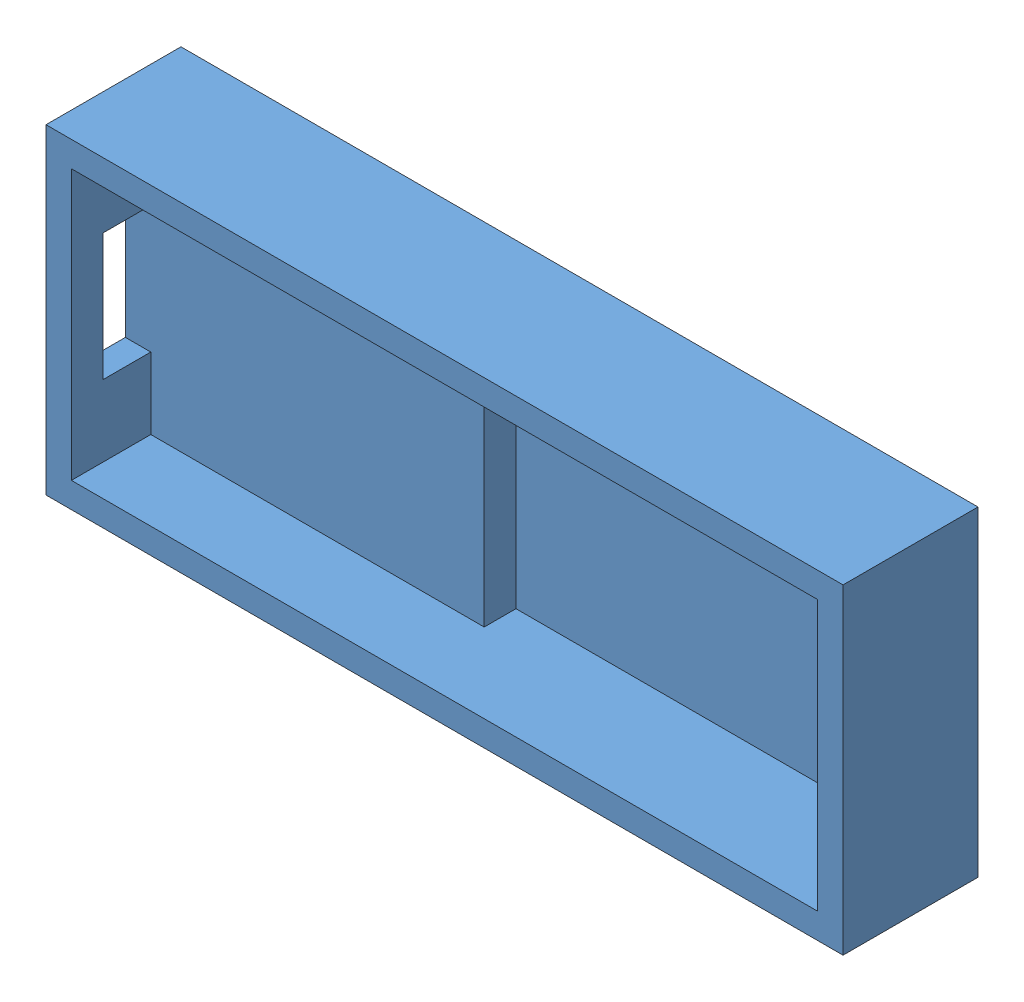
SolidWorks assembly Assem1, configuration Default. Lengths in mm.
Overall size (50.38 20.2 8.5).
2 component instances, 2 part files, 1 mates.
Components (placement in the parent):
- PCB-1: PCB [Default] at (13.731 0 0) size (46.35 16.2 1.7)
- Bottom-1: Bottom [Default] at (11.539 0 -3.3604) size (50.2 20.2 8.5)
Mates (geometry in assembly coordinates):
- Coincident1: coincident aligned: plane of PCB-1 through (13.731 0 0) normal (0 1 0); plane of Bottom-1 through (11.539 0 -3.3604) normal (0 1 0)
